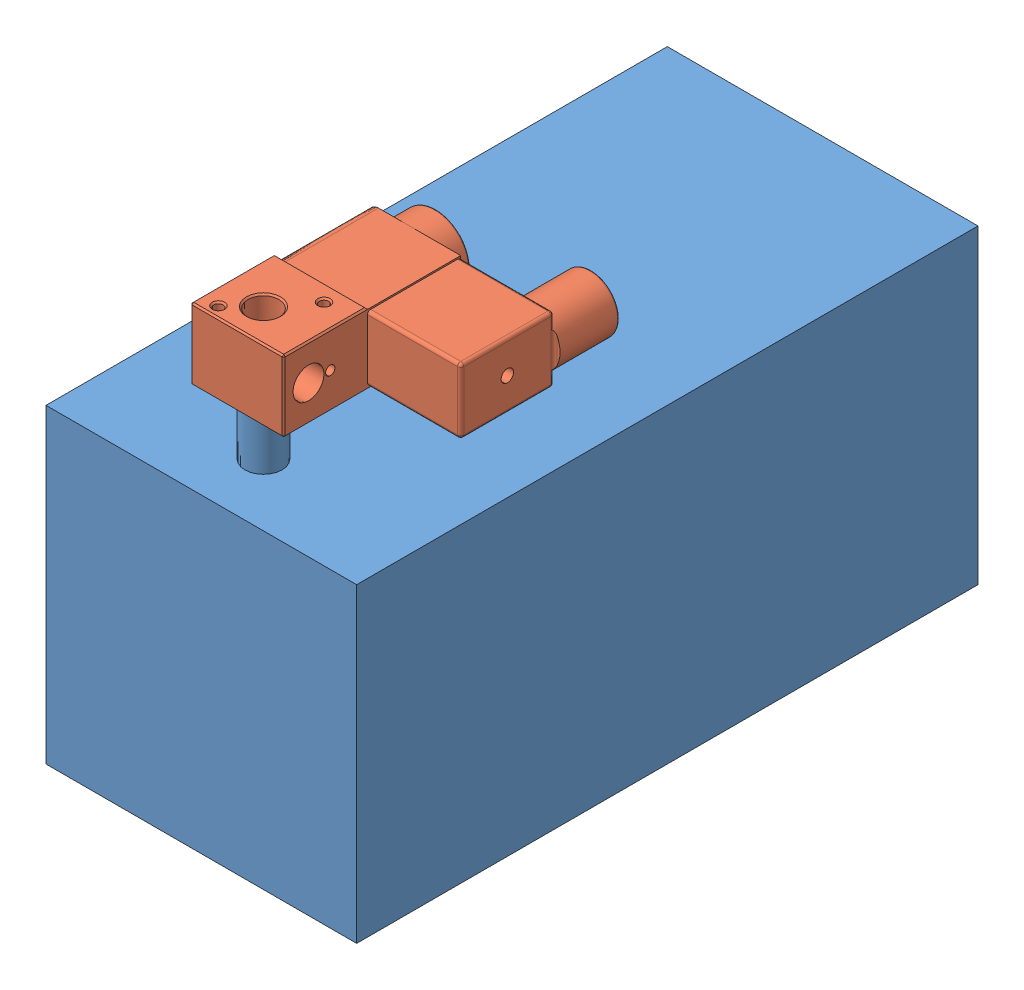
SolidWorks assembly système_ballon, configuration Défaut. Lengths in mm.
Overall size (100 142.5 200).
2 component instances, 2 part files, 3 mates.
Components (placement in the parent):
- réservoir_nu-1: réservoir_nu [Défaut] at (-77.0681 61.7227 0) size (100 120 200)
- Distributeur_3V1_06-1: Distributeur_3V1_06 [Défaut] at (19.9319 104.2227 133.5) x (-1 0 0) z (0 -1 0) size (62 76 23)
Mates (geometry in assembly coordinates):
- Parallèle1: parallel: plane of réservoir_nu-1 through (-77.0681 61.7227 200) normal (0 1 0); plane of Distributeur_3V1_06-1 through (23.9996 81.2227 138.0079) normal (0 -1 0)
- Coïncidente2: coincident: circle of réservoir_nu-1; circle of Distributeur_3V1_06-1
- Parallèle2: parallel aligned: plane of réservoir_nu-1 through (-77.0681 61.7227 200) normal (-1 0 0); plane of Distributeur_3V1_06-1 through (-40.0681 81.2227 190.5) normal (-1 0 0)
